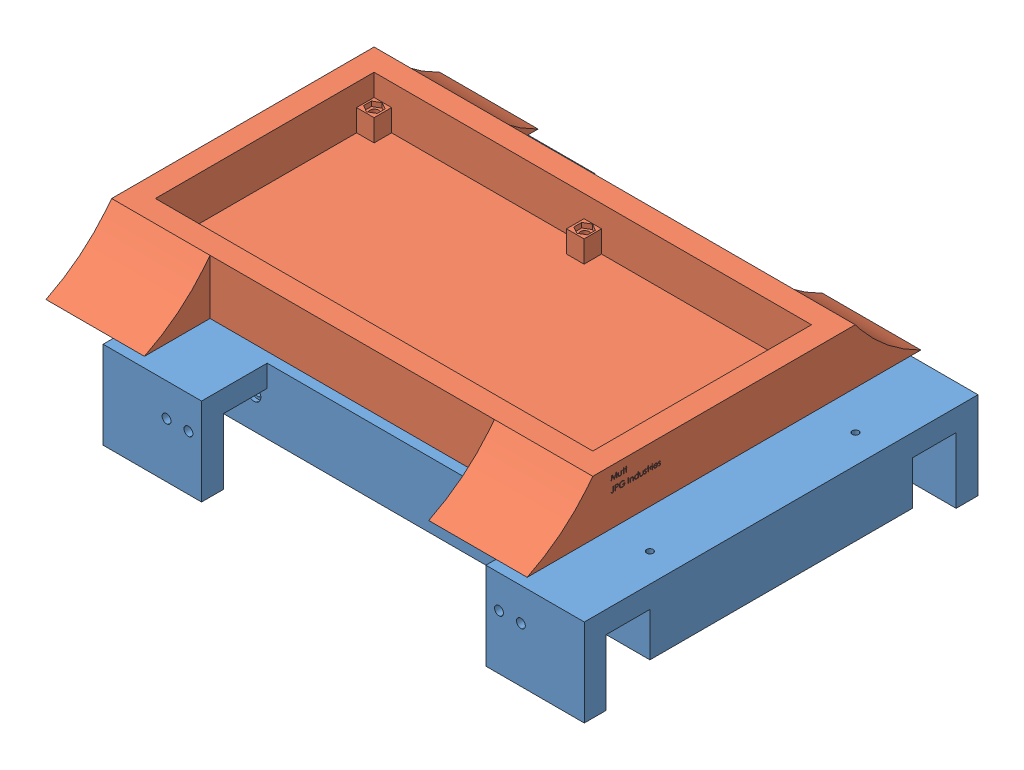
SolidWorks assembly Bearing Mold, configuration Default. Lengths in mm.
Overall size (302.58 104.78 238.59).
2 component instances, 2 part files, 9 mates.
Components (placement in the parent):
- DriveBed-1: DriveBed [Default] at (75.1298 106.2632 168.5887) size (279.4 57.15 228.6)
- ComputationBed-1: ComputationBed [Default] at (102.3037 185.6382 178.3638) size (279.4 31.75 228.6)
Mates (geometry in assembly coordinates):
- Distance2: distance = 6.35 mm anti-aligned: plane of ? through (13.7858 150.3263 94.4917) normal (0 0 -1); plane of DriveBed-1 through (254.8321 125.3132 100.8417) normal (0 0 1)
- Concentric1: concentric anti-aligned: circle of DriveBed-1; circle of ?
- Coincident1: coincident anti-aligned: plane of DriveBed-1 through (254.8321 125.3132 100.8417) normal (0 0 1); plane of ? through (12.2658 113.8795 100.8417) normal (0 0 -1)
- Concentric2: concentric anti-aligned: circle of DriveBed-1; circle of ?
- Concentric3: concentric aligned: circle of DriveBed-1; circle of ?
- Concentric5: concentric: circle of ?; circle of ?
- Coincident3: coincident anti-aligned: plane of ? through (7.1867 135.4656 100.8417) normal (0 0 1); plane of ? through (24.2148 125.5204 100.8417) normal (0 0 -1)
- Concentric6: concentric aligned: circle of ?; circle of ?
- Distance4: distance = 6.35 mm aligned: plane of ? through (6.1031 135.5312 107.1917) normal (0 0 1); plane of DriveBed-1 through (254.8321 112.6132 100.8417) normal (0 0 1)
